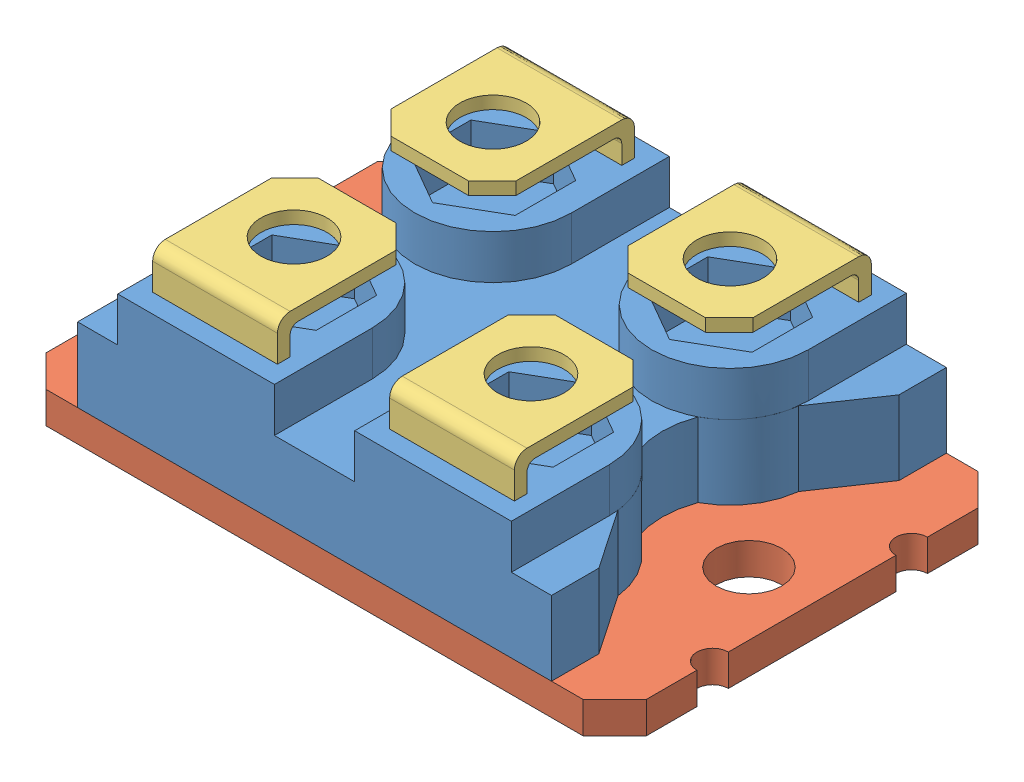
SolidWorks assembly sot-227b_assy, configuration Default. Lengths in mm.
Overall size (38 12 25).
6 component instances, 3 part files, 15 mates.
Components (placement in the parent):
- sot-227b-1: sot-227b [Default] at (-1.7397 -8.008 4.112) size (30 7.5 25)
- sot-227b_baseplate-1: sot-227b_baseplate [Default] at (-5.7397 -10.008 4.112) size (38 2 25)
- sot-227b_prong-1: sot-227b_prong [Default] at (1.8103 -0.508 2.912) x (0 0 -1) z (0 -1 0) size (9 7.9 2.5)
- sot-227b_prong-2: sot-227b_prong [Default] at (9.7103 -0.508 -19.688) x (0 0 1) z (0 -1 0) size (9 7.9 2.5)
- sot-227b_prong-3: sot-227b_prong [Default] at (24.7103 -0.508 -19.688) x (0 0 1) z (0 -1 0) size (9 7.9 2.5)
- sot-227b_prong-4: sot-227b_prong [Default] at (16.8103 -0.508 2.912) x (0 0 -1) z (0 -1 0) size (9 7.9 2.5)
Mates (geometry in assembly coordinates):
- Coincident1: coincident anti-aligned: plane of sot-227b-1 through (5.7603 -8.008 -2.088) normal (0 -1 0); plane of sot-227b_baseplate-1 through (-1.7397 -8.008 -8.388) normal (0 1 0)
- Coincident2: coincident aligned: line of sot-227b-1 through (-1.7397 -8.008 4.112) axis (1 0 0); line of sot-227b_baseplate-1 through (-3.7397 -8.008 4.112) axis (1 0 0)
- Distance1: distance = 4 mm: line of sot-227b_baseplate-1 through (-5.7397 -8.008 -1.088) axis (0 0 1); line of sot-227b-1 through (-1.7397 -8.008 4.112) axis (0 0 -1)
- Coincident4: coincident anti-aligned: plane of sot-227b-1 through (5.7603 -0.508 -2.088) normal (0 1 0); plane of sot-227b_prong-1 through (9.7103 -0.508 2.912) normal (0 -1 0)
- Distance2: distance = 1.2 mm: line of sot-227b_prong-1 through (9.7103 -0.508 2.912) axis (-1 0 0); line of sot-227b-1 through (0.8003 -0.508 4.112) axis (1 0 0)
- Distance4: distance = 1.01 mm: line of sot-227b_prong-1 through (9.7103 -0.508 2.912) axis (0 0 -1); line of sot-227b-1 through (10.7203 -0.508 4.112) axis (0 0 -1)
- Distance6: distance = 1.01 mm: line of sot-227b_prong-2 through (9.7103 -0.508 -19.688) axis (0 0 1); line of sot-227b-1 through (10.7203 -0.508 -14.688) axis (0 0 -1)
- Coincident20: coincident anti-aligned: plane of sot-227b_prong-2 through (1.8103 -0.508 -19.688) normal (0 -1 0); plane of sot-227b-1 through (5.7603 -0.508 -14.688) normal (0 1 0)
- Distance13: distance = 1.2 mm aligned: plane of sot-227b_prong-2 through (1.8103 -0.508 -19.688) normal (0 0 -1); plane of sot-227b-1 through (-1.7397 -3.308 -20.888) normal (0 0 -1)
- Coincident23: coincident anti-aligned: plane of sot-227b-1 through (20.7603 -0.508 -14.688) normal (0 1 0); plane of sot-227b_prong-3 through (16.8103 -0.508 -19.688) normal (0 -1 0)
- Distance15: distance = 1.01 mm: line of sot-227b_prong-3 through (24.7103 -0.508 -19.688) axis (0 0 1); line of sot-227b-1 through (25.7203 -0.508 -14.688) axis (0 0 -1)
- Distance16: distance = 1.2 mm aligned: plane of sot-227b_prong-3 through (16.8103 -0.508 -19.688) normal (0 0 -1); plane of sot-227b-1 through (-1.7397 -3.308 -20.888) normal (0 0 -1)
- Coincident27: coincident anti-aligned: plane of sot-227b-1 through (20.7603 -0.508 -2.088) normal (0 1 0); plane of sot-227b_prong-4 through (24.7103 -0.508 2.912) normal (0 -1 0)
- Distance18: distance = 1.2 mm aligned: plane of sot-227b_prong-4 through (24.7103 -0.508 2.912) normal (0 0 1); plane of sot-227b-1 through (-1.7397 -3.308 4.112) normal (0 0 1)
- Distance20: distance = 1.01 mm: line of sot-227b_prong-4 through (16.8103 -0.508 2.912) axis (0 0 -1); line of sot-227b-1 through (15.8003 -0.508 -2.088) axis (0 0 1)
